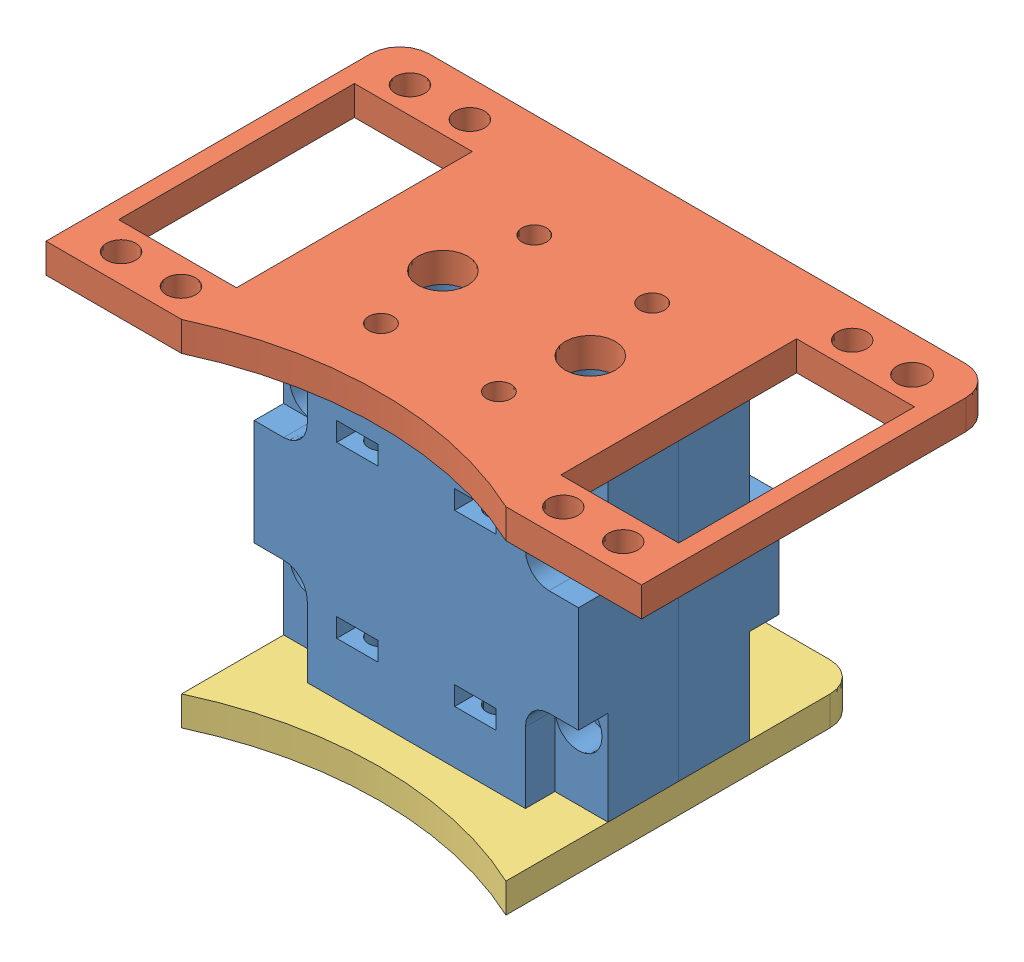
SolidWorks assembly ASSCENCEUR, configuration Default. Lengths in mm.
Overall size (101 60 60).
4 component instances, 3 part files, 10 mates.
Components (placement in the parent):
- guidage-1: guidage [Défaut] at (7.2529 36.9069 40.1491) size (55 50 17)
- guidage-2: guidage [Défaut] at (7.2529 36.9069 64.1491) x (-1 0 0) z (0 0 -1) size (55 50 17)
- CHADEN-1: CHADEN [Default] at (7.6948 61.9069 53.4979) x (1 0 0) z (0 1 0) size (101 60 5)
- CHDENLOUTA-1: CHDENLOUTA [Default] at (7.1705 6.9069 51.6293) x (1 0 0) z (0 1 0) size (55 60 5)
Mates (geometry in assembly coordinates):
- Coincident1: coincident anti-aligned: plane of guidage-1 through (7.2529 36.9069 52.1491) normal (0 0 1); plane of guidage-2 through (7.2529 36.9069 52.1491) normal (0 0 -1)
- Coincident2: coincident aligned: plane of guidage-1 through (-5.2471 61.9069 52.1491) normal (0 1 0); plane of guidage-2 through (19.7529 61.9069 52.1491) normal (0 1 0)
- Concentric1: concentric anti-aligned: cylinder of guidage-1 through (29.7529 49.9069 35.1491) axis (0 0 1) radius 2.1; cylinder of guidage-2 through (29.7529 49.9069 69.1491) axis (0 0 -1) radius 2.1
- Concentric2: concentric aligned: cylinder of guidage-1 through (-15.2471 23.9069 45.1491) axis (0 0 -1) radius 4; cylinder of guidage-2 through (-15.2471 23.9069 69.1491) axis (0 0 -1) radius 2.1
- Concentric3: concentric anti-aligned: cylinder of guidage-1 through (19.7529 14.4069 52.1491) axis (0 1 0) radius 4.25; cylinder of CHADEN-1 through (19.7529 66.9069 52.1491) axis (0 -1 0) radius 4.25
- Concentric4: concentric anti-aligned: cylinder of guidage-1 through (-5.2471 14.4069 52.1491) axis (0 1 0) radius 4.25; cylinder of CHADEN-1 through (-5.2471 66.9069 52.1491) axis (0 -1 0) radius 4.25
- Coincident3: coincident anti-aligned: plane of guidage-2 through (19.7529 61.9069 52.1491) normal (0 1 0); plane of CHADEN-1 through (7.6948 61.9069 53.4979) normal (0 -1 0)
- Concentric5: concentric aligned: cylinder of CHADEN-1 through (19.7529 66.9069 52.1491) axis (0 -1 0) radius 4.25; cylinder of CHDENLOUTA-1 through (19.7529 11.9069 52.1491) axis (0 -1 0) radius 4.25
- Concentric6: concentric aligned: cylinder of CHADEN-1 through (-5.2471 66.9069 52.1491) axis (0 -1 0) radius 4.25; cylinder of CHDENLOUTA-1 through (-5.2471 11.9069 52.1491) axis (0 -1 0) radius 4.25
- Coincident4: coincident anti-aligned: plane of guidage-2 through (-5.2471 11.9069 52.1491) normal (0 -1 0); plane of CHDENLOUTA-1 through (7.2529 11.9069 140.3568) normal (0 1 0)
